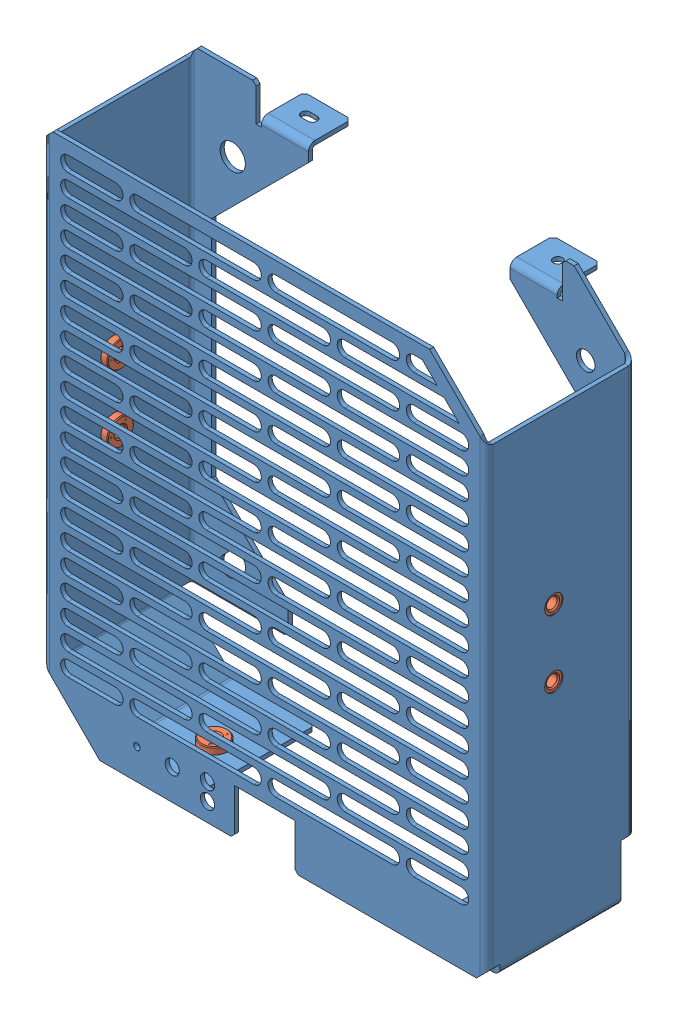
SolidWorks assembly TE-1719_742926-04_SC1-Front-Grill, configuration Default. Lengths in mm.
Overall size (132 155 55.8).
7 component instances, 2 part files, 8 mates.
Components (placement in the parent):
- TE-1719_742926-04_742928-04_MASTER-MODEL_SC1-FRONT-REAR-1: TE-1719_742926-04_742928-04_MASTER-MODEL_SC1-FRONT-REAR [Front_PEM-Nuts] at origin size (132 155 55.8)
- PEM-Nut_S-M4-1ZI-1: PEM-Nut_S-M4-1ZI [Default] at (65.7508 89 -20) x (-1 0 0) z (0 0 -1) size (2.97 7.87 7.87)
- PEM-Nut_S-M4-1ZI-2: PEM-Nut_S-M4-1ZI [Default] at (65.7508 69 -20) x (-1 0 0) z (0 0 -1) size (2.97 7.87 7.87)
- PEM-Nut_S-M4-1ZI-3: PEM-Nut_S-M4-1ZI [Default] at (51 1.4492 -20) x (0 1 0) z (-1 0 0) size (2.97 7.87 7.87)
- PEM-Nut_S-M4-1ZI-8: PEM-Nut_S-M4-1ZI [Default] at (-65.7508 89 -20) size (2.97 7.87 7.87)
- PEM-Nut_S-M4-1ZI-9: PEM-Nut_S-M4-1ZI [Default] at (-65.7508 69 -20) size (2.97 7.87 7.87)
- PEM-Nut_S-M4-1ZI-7: PEM-Nut_S-M4-1ZI [Default] at (-35 1.4492 -20) x (0 1 0) z (-1 0 0) size (2.97 7.87 7.87)
Mates (geometry in assembly coordinates):
- Concentric1: concentric anti-aligned: cylinder of TE-1719_742926-04_742928-04_MASTER-MODEL_SC1-FRONT-REAR-1 through (-66 89 -20) axis (1 0 0) radius 2.7178; cylinder of PEM-Nut_S-M4-1ZI-1 through (63.8988 89 -20) axis (-1 0 0) radius 3.935
- Coincident1: coincident aligned: plane of TE-1719_742926-04_742928-04_MASTER-MODEL_SC1-FRONT-REAR-1 through (64.7808 0 0) normal (-1 0 0); circle of PEM-Nut_S-M4-1ZI-2
- Concentric2: concentric anti-aligned: cylinder of TE-1719_742926-04_742928-04_MASTER-MODEL_SC1-FRONT-REAR-1 through (-66 69 -20) axis (1 0 0) radius 2.7178; cylinder of PEM-Nut_S-M4-1ZI-2 through (63.8988 69 -20) axis (-1 0 0) radius 3.935
- Coincident2: coincident aligned: plane of TE-1719_742926-04_742928-04_MASTER-MODEL_SC1-FRONT-REAR-1 through (64.7808 0 0) normal (-1 0 0); circle of PEM-Nut_S-M4-1ZI-1
- Concentric3: concentric anti-aligned: cylinder of TE-1719_742926-04_742928-04_MASTER-MODEL_SC1-FRONT-REAR-1 through (51 156.2 -20) axis (0 -1 0) radius 2.7178; cylinder of PEM-Nut_S-M4-1ZI-3 through (51 3.3012 -20) axis (0 1 0) radius 3.935
- Coincident3: coincident aligned: plane of TE-1719_742926-04_742928-04_MASTER-MODEL_SC1-FRONT-REAR-1 through (0 2.4192 0) normal (0 1 0); circle of PEM-Nut_S-M4-1ZI-3
- Concentric4: concentric anti-aligned: cylinder of TE-1719_742926-04_742928-04_MASTER-MODEL_SC1-FRONT-REAR-1 through (-35 156.2 -20) axis (0 -1 0) radius 2.7178; cylinder of PEM-Nut_S-M4-1ZI-7 through (-35 3.3012 -20) axis (0 1 0) radius 3.935
- Coincident4: coincident aligned: plane of TE-1719_742926-04_742928-04_MASTER-MODEL_SC1-FRONT-REAR-1 through (-0.3571 2.4192 0) normal (0 1 0); circle of PEM-Nut_S-M4-1ZI-7
